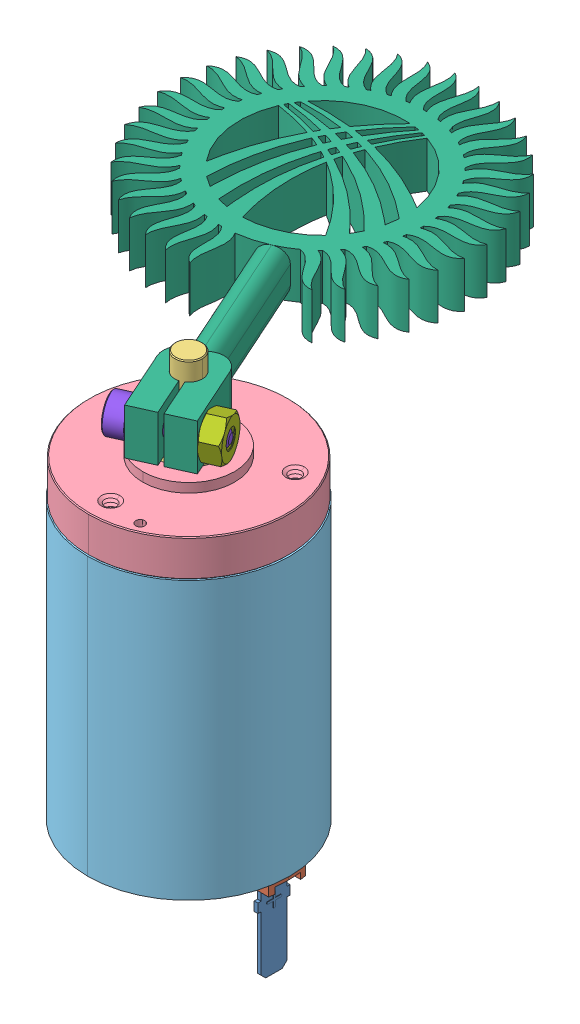
SolidWorks assembly PendulumAssembly, configuration Default. Lengths in mm.
Overall size (50.75 54.2 60.16).
9 component instances, 8 part files, 9 mates.
Components (placement in the parent):
- motor.stp-1: motor.stp [Default] x (0 -1 0) z (0 0 1) size (54.2 22 22)
  - 0.stp-1: 0.stp [Default] at origin size (13.5 18.65 3.5)
  - 0-0.stp-1: 0-0.stp [Default] at origin size (2.35 21.8 21.35)
  - 0-1.stp-1: 0-1.stp [Default] at origin size (49.15 8 8)
  - 0-2.stp-1: 0-2.stp [Default] at origin size (5 21.8 21.8)
  - 0-3.stp-1: 0-3.stp [Default] at origin size (32.6 22 22)
- Pendulum-1: Pendulum [Default] at (-3.9654 3 -1.5086) x (0.912331 0 -0.409453) z (0.409453 0 0.912331) size (32.61 5 51.3)
- nut-1: nut [90725A010] at (5.2871 5.5 2.0115) x (0.276089 0.738469 0.615174) z (0.302368 -0.674288 0.673728) size (4 2.31 4.62)
- screw-1: screw [91290A015] at (6.1995 5.5 1.6021) x (0.288825 -0.708817 0.643551) z (0.912331 0 -0.409453) size (3.8 3.8 10.11)
Mates (geometry in assembly coordinates):
- Coincident1: coincident: plane of motor.stp-1 through (0 0 0) normal (0 -1 0)
- Coincident2: coincident: plane of motor.stp-1 through (0 0 0) normal (0 0 1)
- Coincident3: coincident: plane of motor.stp-1 through (0 0 0) normal (1 0 0)
- Concentric1: concentric aligned: cylinder of motor.stp-1/0-1.stp-1 through (0 2.775 0) axis (0 -1 0) radius 1.5; cylinder of Pendulum-1 through (0 8 0) axis (0 -1 0) radius 1.5
- Distance1: distance = 2 mm aligned: plane of motor.stp-1/0-1.stp-1 through (0.75 10 0) normal (0 1 0); plane of Pendulum-1 through (-11.8741 8 -26.4576) normal (0 1 0)
- Concentric2: concentric anti-aligned: cylinder of Pendulum-1 through (4.3748 5.5 2.421) axis (-0.912331 0 0.409453) radius 1; line of screw-1 through (-5.1055 5.5 6.6757) axis (0.912331 0 -0.409453)
- Coincident6: coincident anti-aligned: plane of Pendulum-1 through (-3.9654 8 -1.5086) normal (-0.912331 0 0.409453); plane of screw-1 through (-1.0992 5.5 4.8777) normal (0.912331 0 -0.409453)
- Coincident10: coincident anti-aligned: line of nut-1 through (9.4667 5.5 0.1357) axis (-0.912331 0 0.409453); line of screw-1 through (-5.1055 5.5 6.6757) axis (0.912331 0 -0.409453)
- Coincident11: coincident anti-aligned: plane of Pendulum-1 through (1.5086 8 -3.9654) normal (0.912331 0 -0.409453); plane of nut-1 through (3.4735 4.8017 0.4127) normal (-0.912331 0 0.409453)
